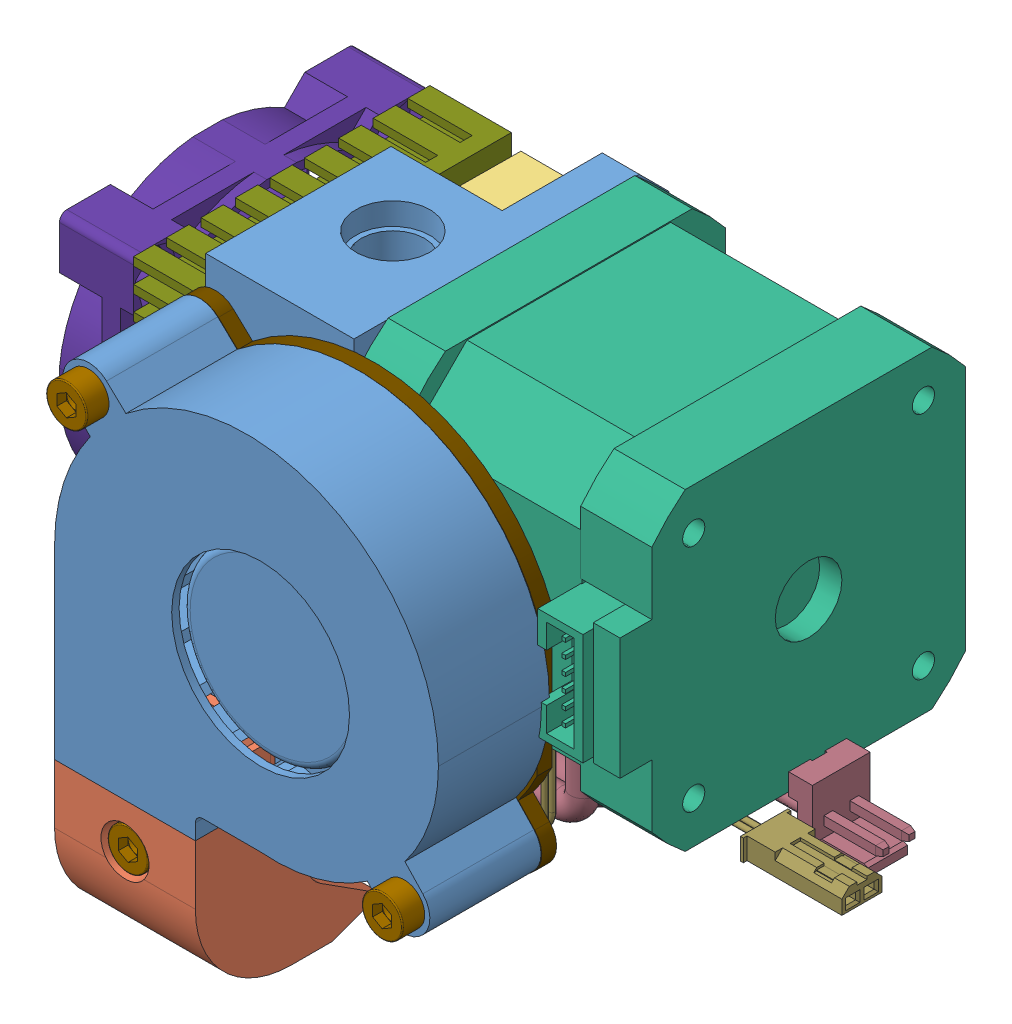
SolidWorks assembly SubEnsamblaje Extrusor BQ V1, configuration Predeterminado. Lengths in mm.
Overall size (94.29 74.68 65.03).
31 component instances, 20 part files, 34 mates.
Components (placement in the parent):
- SubEnsamblaje_CuerpoExtrusor_BQ-1: SubEnsamblaje_CuerpoExtrusor_BQ [Predeterminado] at (-13.7983 -23.75 18.2917) x (1 0 0) z (0 1 0) size (60.1 48.13 47.65)
  - extruder-body-part-1: extruder-body-part [Predeterminado] at (0.4154 8.1053 -127.88) size (20 45 47.5)
  - lever-shaft-final-1: lever-shaft-final [Predeterminado] at (0.4154 8.1053 -127.88) size (20 3 3)
  - extruder-lever-final-1: extruder-lever-final [Predeterminado] at (0.4154 6.5726 -128.1067) x (1 0 0) z (0 0.00823 0.999966) size (15 42.5 16)
  - Extruder-lever-623zz-bearing-1: Extruder-lever-623zz-bearing [Predeterminado] at (0.1654 -10.2804 -129.3004) x (1 0 0) z (0 0.102182 0.994766) size (4 10 10)
  - ISO-10642-M3x12-bolt-1-2: ISO-10642-M3x12-bolt-1 [Predeterminado] at (0.1654 6.5726 -128.1067) x (1 0 0) z (0 0.00823 0.999966) size (12.11 6.05 6.05)
  - Extruder-motor-Nema-17-40mm-with-connector-2: Extruder-motor-Nema-17-40mm-with-connector [Predeterminado] at (0.4154 8.1053 -127.88) size (60.1 48 42.3)
  - Extruder-drive-gear-2: Extruder-drive-gear [Predeterminado] at (0.4154 8.1053 -127.88) size (11 12.5 12.5)
  - extruder-setscrew2-1: extruder-setscrew2 [Predeterminado] at (4.4154 -142.59 40.1847) x (1 0 0) z (0 1 0) size (3 3 3)
  - socket head cap screw_iso-3: socket head cap screw_iso [ISO 4762 M3 x 20 --- 20N] at (-9.4012 12.54 34.75) size (23 5.5 5.5)
  - socket head cap screw_iso-4: socket head cap screw_iso [ISO 4762 M3 x 20 --- 20N] at (-9.4012 -18.46 34.75) size (23 5.5 5.5)
- SubEnsamblaje HotEnd BQ V1-1: SubEnsamblaje HotEnd BQ V1 [Predeterminado] at (-1.5995 -18 14.2517) size (70.79 49 19)
  - hotend-heater-block-main-2: hotend-heater-block-main [Predeterminado] at (-11.7834 -133.63 -4.0653) x (1 0 0) z (0 1 0) size (19 19 10)
  - Hotend-main-tube-final-1: Hotend-main-tube-final [Predeterminado] at (-11.7834 -133.63 -4.0653) x (1 0 0) z (0 1 0) size (10 10 36)
  - hotend-thermistor-final-1: hotend-thermistor-final [Predeterminado] at (-11.7834 -133.63 -4.0653) x (1 0 0) z (0 1 0) size (55.29 6.4 19.1)
  - hotend-heater-cartridge-1: hotend-heater-cartridge [Predeterminado] at (-11.7834 -133.63 -4.0653) x (1 0 0) z (0 1 0) size (68.81 7.8 23.9)
  - extruder-setscrew2-1: extruder-setscrew2 [Predeterminado] at (-17.1285 -133.63 -2.6635) x (0.849368 0 -0.527801) z (0 1 0) size (3 3 3)
  - hot-end-nozzle-final-1: hot-end-nozzle-final [Predeterminado] at (3.84 -133.63 6.6468) x (0.384008 0 0.92333) z (0 1 0) size (7 8.88 13)
  - extruder-ptfe-tube-final-1: extruder-ptfe-tube-final [Predeterminado] at (-11.7834 175.08 30.0653) x (1 0 0) z (0 -1 0) size (4 4 25.2)
- extruder-heat-sink-final-1: extruder-heat-sink-final [Predeterminado] at (-13.3829 -151.63 10.1864) x (1 0 0) z (0 1 0) size (11 40 40)
- fan-40x40mm-final-1: fan-40x40mm-final [Predeterminado] at (-13.3495 32.0653 -151.3786) size (10 40 40)
- socket head cap screw_iso-1: socket head cap screw_iso [ISO 4762 M3 x 25 --- 18N] at (-44.3595 5 37.2412) size (28 5.5 5.5)
- socket head cap screw_iso-2: socket head cap screw_iso [ISO 4762 M3 x 25 --- 18N] at (-44.3595 5 5.2517) size (28 5.5 5.5)
- Extruder-blower-support-final-1: Extruder-blower-support-final [Predeterminado] at (-13.3829 -151.63 10.1865) x (1 0 0) z (0 1 0) size (50.65 2 61.4)
- ISO-10642-M3x12-bolt-1-1: ISO-10642-M3x12-bolt-1 [Predeterminado] at (158.5305 40.3153 41.9666) x (0 0 1) z (-1 0 0) size (12.11 6.05 6.05)
- ISO-10642-M3x12-bolt-1-2: ISO-10642-M3x12-bolt-1 [Predeterminado] at (158.5305 25.3153 41.9666) x (0 0 1) z (-1 0 0) size (12.11 6.05 6.05)
- Extruder-Blower-50x50-1: Extruder-Blower-50x50 [Predeterminado] at (-13.6096 -151.6375 10.1863) x (0.999999 -0.001166 0) z (0.001166 0.999999 0) size (51.8 15 51.03)
- air-nozzle-1: air-nozzle [Predeterminado] at (-13.4356 -151.6357 9.7864) x (1 0 0) z (0 1 0) size (19 25 26)
- socket head cap screw_iso-3: socket head cap screw_iso [ISO 4762 M3 x 16 --- 16N] at (-19.8995 42.85 65) x (0 0 -1) z (1 0 0) size (19 5.5 5.5)
- socket head cap screw_iso-4: socket head cap screw_iso [ISO 4762 M3 x 16 --- 16N] at (22.7005 4.45 65) x (0 0 -1) z (1 0 0) size (19 5.5 5.5)
- socket head cap screw_iso-6: socket head cap screw_iso [ISO 4762 M3 x 16 --- 16N] at (-14.9995 -8.35 61.6) x (0 0 -1) z (1 0 0) size (19 5.5 5.5)
Mates (geometry in assembly coordinates):
- Coincidente1: coincident: plane of SubEnsamblaje_CuerpoExtrusor_BQ-1/extruder-body-part-1 through (-3.5995 0 45) normal (0 -1 0); plane of assembly through (0 0 0) normal (0 1 0)
- Coincidente2: coincident anti-aligned: plane of SubEnsamblaje_CuerpoExtrusor_BQ-1/extruder-body-part-1 through (-3.5995 0 0) normal (0 0 -1); plane of assembly through (0 0 0) normal (0 0 1)
- Bloquear1: lock: unknown of ?; unknown of ?
- Coincidente3: coincident anti-aligned: plane of SubEnsamblaje_CuerpoExtrusor_BQ-1/extruder-body-part-1 through (-3.5995 0 45) normal (0 -1 0); circle of SubEnsamblaje HotEnd BQ V1-1/Hotend-main-tube-final-1
- Paralelo1: parallel aligned: plane of SubEnsamblaje_CuerpoExtrusor_BQ-1/extruder-body-part-1 through (-23.5995 0 45) normal (-1 0 0); plane of SubEnsamblaje HotEnd BQ V1-1/hotend-heater-block-main-2 through (-20.5995 -18 14.2517) normal (-1 0 0)
- Concéntrica2: concentric anti-aligned: cylinder of SubEnsamblaje_CuerpoExtrusor_BQ-1/extruder-body-part-1 through (-23.5995 5 37.2517) axis (-1 0 0) radius 1.23; cylinder of extruder-heat-sink-final-1 through (-23.5995 5 37.2517) axis (1 0 0) radius 1.75
- Concéntrica3: concentric anti-aligned: cylinder of SubEnsamblaje_CuerpoExtrusor_BQ-1/extruder-body-part-1 through (-23.5995 5 5.2517) axis (-1 0 0) radius 1.23; cylinder of extruder-heat-sink-final-1 through (-23.5995 5 5.2517) axis (1 0 0) radius 1.75
- Coincidente5: coincident anti-aligned: plane of SubEnsamblaje_CuerpoExtrusor_BQ-1/extruder-body-part-1 through (-23.5995 0 45) normal (-1 0 0); plane of extruder-heat-sink-final-1 through (-23.5995 1 41.2517) normal (1 0 0)
- Concéntrica4: concentric anti-aligned: cylinder of extruder-heat-sink-final-1 through (-23.5995 5 5.2517) axis (1 0 0) radius 1.75; cylinder of fan-40x40mm-final-1 through (-44.5995 5 5.2517) axis (-1 0 0) radius 2.15
- Coincidente6: coincident anti-aligned: plane of extruder-heat-sink-final-1 through (-34.5995 1 41.2517) normal (-1 0 0); plane of fan-40x40mm-final-1 through (-34.5995 1.9948 1.2464) normal (1 0 0)
- Paralelo5: parallel aligned: plane of extruder-heat-sink-final-1 through (-23.5995 41 41.2517) normal (0 0 1); plane of fan-40x40mm-final-1 through (-34.5995 39.9948 41.2464) normal (0 0 1)
- Concéntrica13: concentric aligned: cylinder of fan-40x40mm-final-1 through (-44.5995 5 37.2412) axis (-1 0 0) radius 2.15; cylinder of socket head cap screw_iso-1 through (-76.1095 5 37.2412) axis (-1 0 0) radius 2.75
- Coincidente8: coincident anti-aligned: plane of fan-40x40mm-final-1 through (-41.3595 2.2423 34.4835) normal (-1 0 0); plane of socket head cap screw_iso-1 through (-41.3595 7.75 37.2412) normal (1 0 0)
- Concéntrica14: concentric aligned: cylinder of fan-40x40mm-final-1 through (-44.5995 5 5.2517) axis (-1 0 0) radius 2.15; cylinder of socket head cap screw_iso-2 through (-76.1095 5 5.2517) axis (-1 0 0) radius 2.75
- Coincidente9: coincident: plane of fan-40x40mm-final-1 through (-41.3595 7.7577 2.494) normal (-1 0 0); plane of socket head cap screw_iso-2 through (-41.3595 7.75 5.2517) normal (1 0 0)
- Coincidente10: coincident anti-aligned: plane of SubEnsamblaje_CuerpoExtrusor_BQ-1/extruder-body-part-1 through (-3.5995 47.5 45) normal (0 0 1); plane of Extruder-blower-support-final-1 through (25.6005 32.25 45) normal (0 0 -1)
- Concéntrica15: concentric aligned: cylinder of SubEnsamblaje_CuerpoExtrusor_BQ-1/extruder-body-part-1 through (-19.5995 17.75 45) axis (0 0 1) radius 1.23; cylinder of Extruder-blower-support-final-1 through (-19.5995 17.75 47) axis (0 0 1) radius 1.7
- Concéntrica16: concentric aligned: cylinder of SubEnsamblaje_CuerpoExtrusor_BQ-1/extruder-body-part-1 through (-19.5995 2.75 45) axis (0 0 1) radius 1.23; cylinder of Extruder-blower-support-final-1 through (-19.5995 2.75 47) axis (0 0 1) radius 1.7
- Concéntrica19: concentric anti-aligned: cylinder of SubEnsamblaje_CuerpoExtrusor_BQ-1/extruder-body-part-1 through (-19.5995 17.75 45) axis (0 0 1) radius 1.23; cylinder of ISO-10642-M3x12-bolt-1-1 through (-19.5995 17.75 45.3) axis (0 0 -1) radius 1.5
- Coincidente11: coincident aligned: plane of Extruder-blower-support-final-1 through (25.6005 32.25 47) normal (0 0 1); plane of ISO-10642-M3x12-bolt-1-1 through (-19.5995 17.75 47) normal (0 0 1)
- Concéntrica21: concentric anti-aligned: cylinder of SubEnsamblaje_CuerpoExtrusor_BQ-1/extruder-body-part-1 through (-19.5995 2.75 45) axis (0 0 1) radius 1.23; cylinder of ISO-10642-M3x12-bolt-1-2 through (-19.5995 2.75 45.3) axis (0 0 -1) radius 1.5
- Coincidente12: coincident aligned: plane of Extruder-blower-support-final-1 through (25.6005 32.25 47) normal (0 0 1); plane of ISO-10642-M3x12-bolt-1-2 through (-19.5995 2.75 47) normal (0 0 1)
- Coincidente13: coincident anti-aligned: plane of Extruder-blower-support-final-1 through (25.6005 32.25 47) normal (0 0 1); plane of Extruder-Blower-50x50-1 through (22.7803 9.363 47) normal (0 0 -1)
- Concéntrica22: concentric aligned: cylinder of Extruder-blower-support-final-1 through (-19.8995 42.85 47) axis (0 0 1) radius 1.23; cylinder of Extruder-Blower-50x50-1 through (-19.8995 42.85 62) axis (0 0 1) radius 2
- Paralelo10: parallel anti-aligned: line of Extruder-blower-support-final-1 through (-24.4043 22.75 47) axis (0 -1 0); line of Extruder-Blower-50x50-1 through (-24.4995 -2.35 47) axis (0 1 0)
- Ancho1: width aligned: plane of air-nozzle-1 through (-22.8995 -2.35 50) normal (-1 0 0); plane of air-nozzle-1 through (-7.0995 -2.35 48.75) normal (1 0 0); plane of Extruder-Blower-50x50-1 through (-6.4995 -0.65 48.8) normal (-1 0 0); plane of Extruder-Blower-50x50-1 through (-23.4995 22.75 48.8) normal (1 0 0)
- Coincidente18: coincident anti-aligned: plane of Extruder-Blower-50x50-1 through (-24.4995 -2.35 47) normal (0 -1 0); plane of air-nozzle-1 through (-23.4995 -2.35 47) normal (0 1 0)
- Coincidente20: coincident anti-aligned: plane of Extruder-blower-support-final-1 through (25.6005 32.25 47) normal (0 0 1); plane of air-nozzle-1 through (-13.4356 -151.6357 47) normal (0 0 -1)
- Concéntrica31: concentric aligned: cylinder of Extruder-Blower-50x50-1 through (-19.8995 42.85 62) axis (0 0 1) radius 2; cylinder of socket head cap screw_iso-3 through (-19.8995 42.85 96.75) axis (0 0 1) radius 2.75
- Coincidente21: coincident anti-aligned: plane of Extruder-Blower-50x50-1 through (22.7803 9.363 62) normal (0 0 1); plane of socket head cap screw_iso-3 through (-19.8995 45.6 62) normal (0 0 -1)
- Concéntrica32: concentric aligned: cylinder of Extruder-Blower-50x50-1 through (22.7005 4.45 62) axis (0 0 1) radius 2; cylinder of socket head cap screw_iso-4 through (22.7005 4.45 96.75) axis (0 0 1) radius 2.75
- Coincidente22: coincident anti-aligned: plane of Extruder-Blower-50x50-1 through (22.7803 9.363 62) normal (0 0 1); plane of socket head cap screw_iso-4 through (22.7005 7.2 62) normal (0 0 -1)
- Concéntrica34: concentric aligned: cylinder of air-nozzle-1 through (-14.9995 -8.35 62) axis (0 0 1) radius 3.25; cylinder of socket head cap screw_iso-6 through (-14.9995 -8.35 93.35) axis (0 0 1) radius 2.75
- Coincidente24: coincident anti-aligned: plane of air-nozzle-1 through (-13.2995 -8.35 58.6) normal (0 0 1); plane of socket head cap screw_iso-6 through (-14.9995 -5.6 58.6) normal (0 0 -1)
